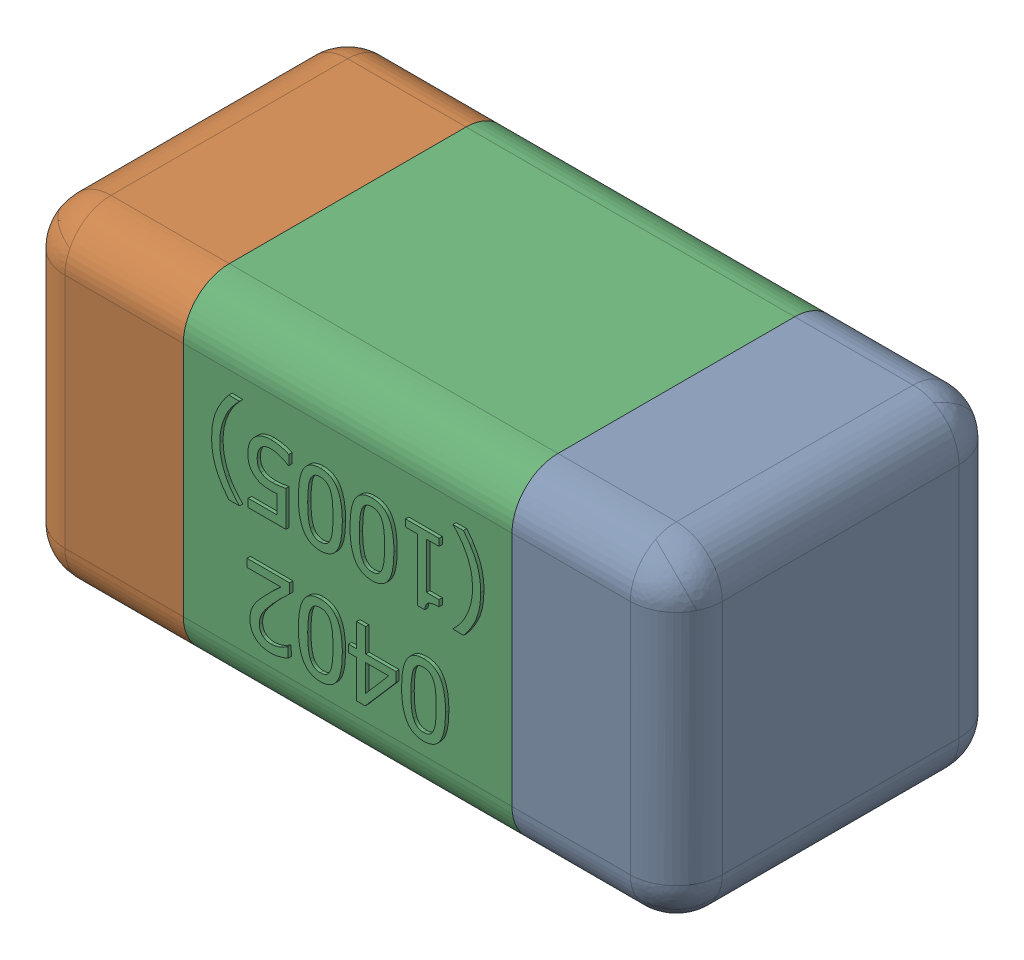
SolidWorks assembly C28, configuration Standard. Lengths in mm.
Overall size (1.01 0.51 0.51).
4 component instances, 3 part files, 0 mates.
Components (placement in the parent):
- C28-subassembly-1-1: C28-subassembly-1 [Standard] at (-10.4001 -10.2 0) x (-1 0 0) z (0 0 1) size (1.01 0.51 0.51)
  - User Library-0402_Cap-1: User Library-0402_Cap [Standard] at origin size (0.26 0.51 0.51)
  - User Library-0402_Cap-1-1: User Library-0402_Cap-1 [Standard] at origin size (0.26 0.5 0.51)
  - User Library-0402_Cap-2-1: User Library-0402_Cap-2 [Standard] at origin size (0.5 0.5 0.51)
